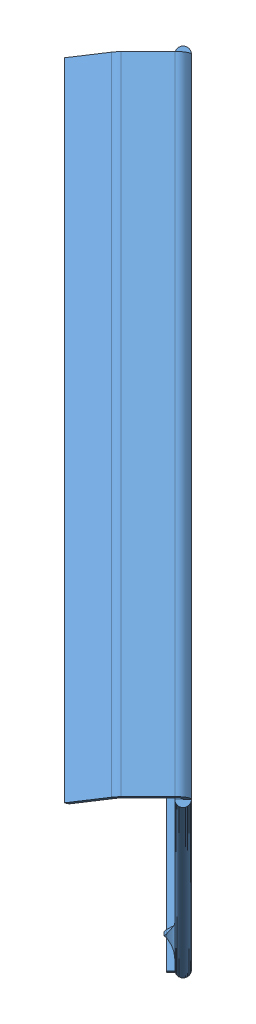
SolidWorks assembly sweet screen, configuration Default. Lengths in mm.
Overall size (283.33 771.18 283.33).
3 component instances, 3 part files, 5 mates.
Components (placement in the parent):
- Frame-1: Frame [Default] at (20.3068 185.0949 880.7989) size (283.33 771.18 283.33)
- glass panel for god screen-1: glass panel for god screen [Default] at (-40.715 166.9153 847.3418) x (0.5 0.707107 0.5) z (-0.707107 0 0.707107) size (147.32 101.6 2.54)
- Button Dial-1: Button Dial [Default] at (-81.6373 96.2697 838.5954) x (0.5 -0.707107 0.5) z (0.5 0.707107 0.5) size (15.23 13.25 15.23)
Mates (geometry in assembly coordinates):
- Coincident1: coincident anti-aligned: plane of Frame-1 through (-52.238 202.5192 839.4109) normal (0.5 -0.707107 0.5); plane of glass panel for god screen-1 through (-89.8686 149.3013 801.7802) normal (-0.5 0.707107 -0.5)
- Coincident4: coincident aligned: plane of Frame-1 through (-53.8269 204.7663 837.8219) normal (-0.707107 0 0.707107); plane of glass panel for god screen-1 through (-42.511 166.9153 849.1378) normal (-0.707107 0 0.707107)
- Coincident5: coincident: line of Frame-1 through (-30.6846 257.9666 883.5602) axis (0.5 -0.707107 0.5); plane of glass panel for god screen-1 through (-16.2086 253.4723 875.4402) normal (0.5 0.707107 0.5)
- Coincident6: coincident: plane of Frame-1 through (5.6576 160.944 895.448) normal (-0.707107 0 0.707107); plane of Button Dial-1 through (-76.8268 110.9926 812.9636) normal (0.707107 0 -0.707107)
- Lock1: lock: unknown of Frame-1; unknown of Button Dial-1
